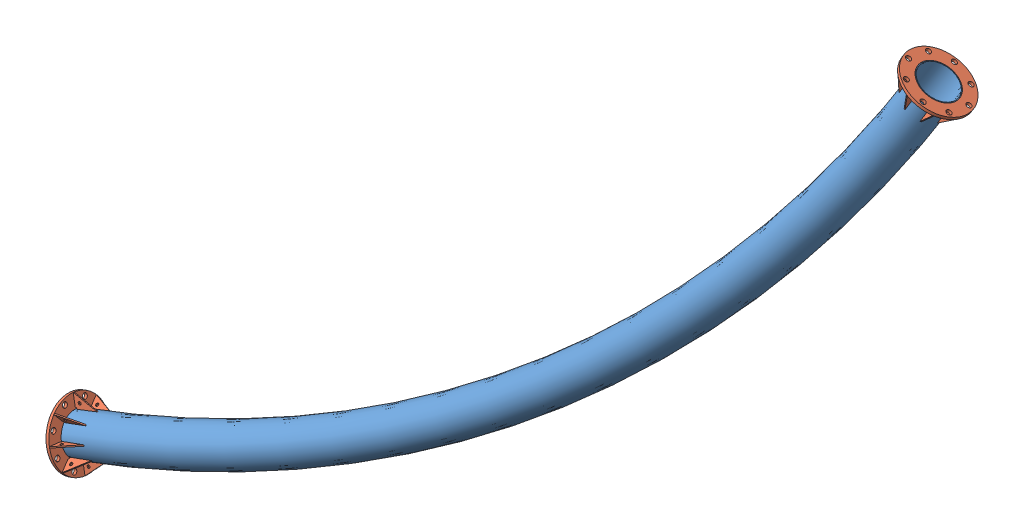
SolidWorks assembly pipe_c_asm, configuration Default. Lengths in mm.
Overall size (3495.18 2972.09 931.51).
3 component instances, 2 part files, 3 mates.
Components (placement in the parent):
- pipe_c^pipe_c_asm-1: pipe_c^pipe_c_asm [Default<As Machined>] at origin size (3377.07 2833.74 741.78) (virtual)
- pipe_flange-1: pipe_flange [Default] at (5240.5926 -3970.6698 3800.0944) x (-0.142192 0.236836 -0.961088) z (0.9506 0.303344 -0.065889) size (279.4 279.4 111.05)
- pipe_flange-2: pipe_flange [Default] at (8516.9964 -1259.0217 3224.9915) x (-0.825192 0.347558 -0.445265) z (-0.463592 -0.867084 0.182342) size (279.4 279.4 111.05)
Mates (geometry in assembly coordinates):
- Concentric13: concentric aligned: circle of pipe_c^pipe_c_asm-1; circle of pipe_flange-2
- Coincident2: coincident aligned: plane of pipe_c^pipe_c_asm-1 through (5240.5926 -3970.6698 3800.0944) normal (-0.9506 -0.303344 0.065889); plane of pipe_flange-1 through (5240.5926 -3970.6698 3800.0944) normal (-0.9506 -0.303344 0.065889)
- Coincident3: coincident aligned: plane of pipe_flange-2 through (8516.9964 -1259.0217 3224.9915) normal (0.463592 0.867084 -0.182342); plane of pipe_c^pipe_c_asm-1 through (8516.9964 -1259.0217 3224.9915) normal (0.463592 0.867084 -0.182342)
